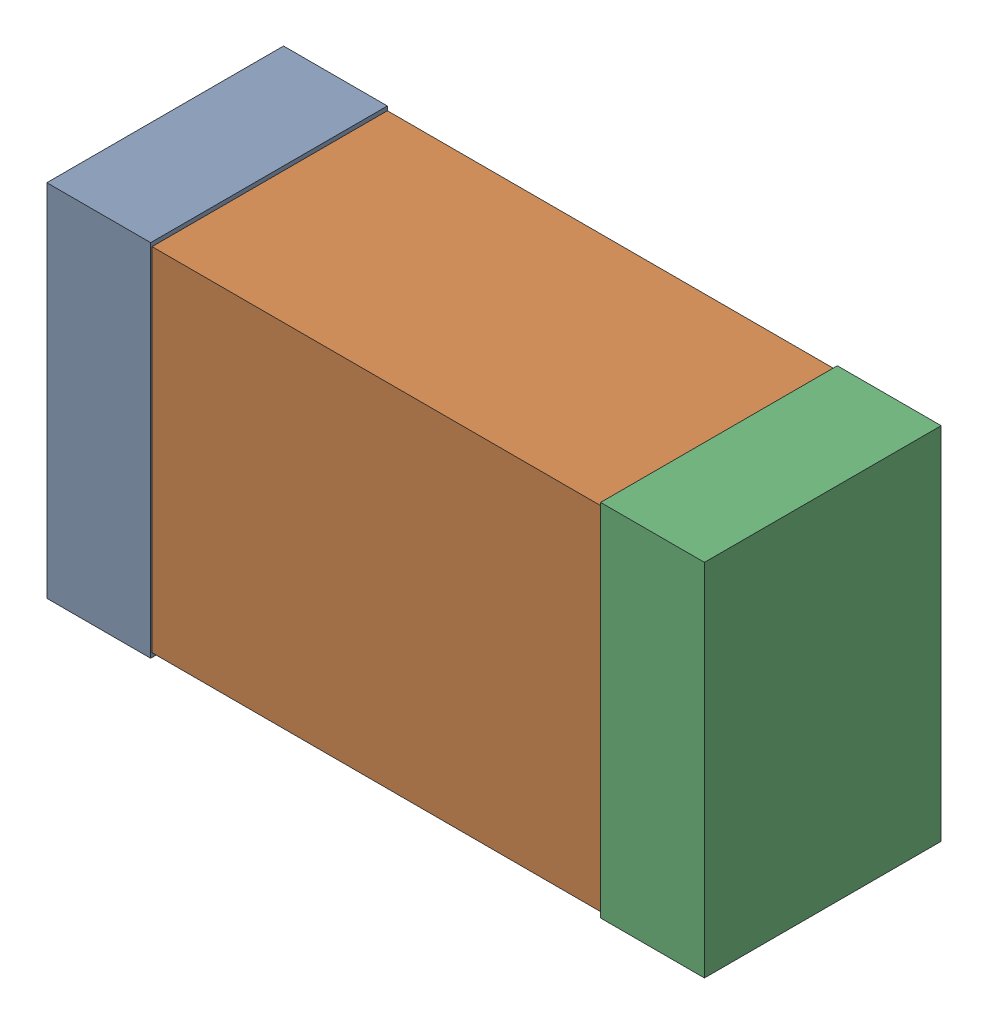
SolidWorks assembly USB01_C6, configuration Default. Lengths in mm.
Overall size (2.38 1.3 0.85).
6 component instances, 2 part files, 0 mates.
Components (placement in the parent):
- 384311232-1: 384311232 [Default] at (148.86 69.723 0) size (0.38 1.3 0.85)
  - Extruded_8-1: Extruded_8 [Default] at origin size (0.38 1.3 0.85)
- 384311360-1: 384311360 [Default] at (149.86 69.723 0) size (2.2 1.27 0.85)
  - Extruded_9-1: Extruded_9 [Default] at origin size (2.2 1.27 0.85)
- 384311232-2: 384311232 [Default] at (150.86 69.723 0) size (0.38 1.3 0.85)
  - Extruded_8-1: Extruded_8 [Default] at origin size (0.38 1.3 0.85)
